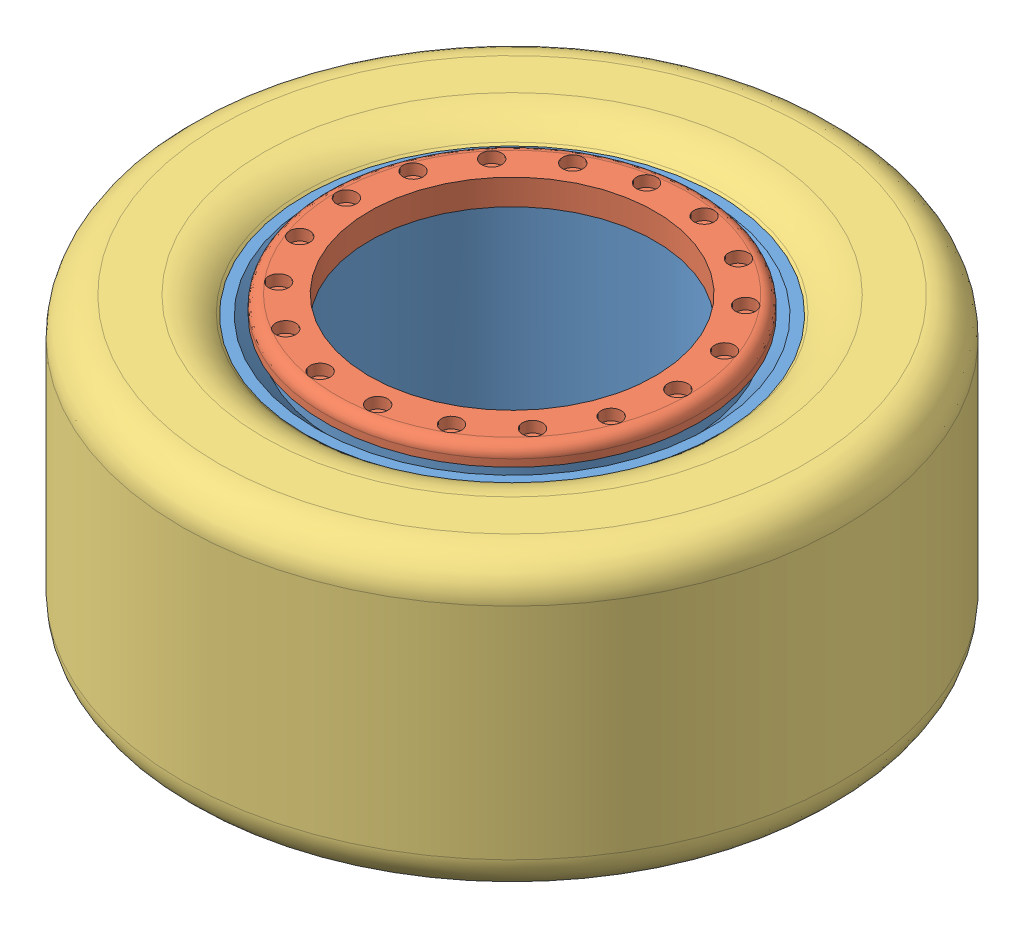
SolidWorks assembly Wheel, configuration Default. Lengths in mm.
Overall size (180 80.5 180).
4 component instances, 3 part files, 9 mates.
Components (placement in the parent):
- Hub-1: Hub [Default] at origin size (113 70.5 113)
- Hub_cover-1: Hub_cover [Default] at (0 70.5 0) x (0.173648 0 -0.984808) z (0.984808 0 0.173648) size (102 7 102)
- Hub_cover-2: Hub_cover [Default] x (-0.766044 0 0.642788) z (0.642788 0 0.766044) size (102 7 102)
- Tire-1: Tire [Default] at (0 -4.75 0) size (180 80 180)
Mates (geometry in assembly coordinates):
- Concentric1: concentric aligned: cylinder of Hub-1 through (0 0 0) axis (0 -1 0) radius 48.5; cylinder of Hub_cover-1 through (0 75.5 0) axis (0 -1 0) radius 39
- Concentric2: concentric anti-aligned: cylinder of Hub-1 through (0 0 0) axis (0 -1 0) radius 48.5; cylinder of Hub_cover-2 through (0 -5 0) axis (0 1 0) radius 39
- Coincident1: coincident anti-aligned: plane of Hub-1 through (0 70.5 -48.5) normal (0 1 0); plane of Hub_cover-1 through (0 70.5 0) normal (0 -1 0)
- Coincident2: coincident anti-aligned: plane of Hub-1 through (0 0 -48.5) normal (0 -1 0); plane of Hub_cover-2 through (0 0 0) normal (0 1 0)
- Concentric4: concentric anti-aligned: cylinder of Hub-1 through (7.8576 65.5 -44.5626) axis (0 1 0) radius 1.5; cylinder of Hub_cover-1 through (7.8576 75.5 -44.5626) axis (0 -1 0) radius 1.5
- Concentric5: concentric anti-aligned: cylinder of Hub-1 through (7.8576 5 -44.5626) axis (0 -1 0) radius 1.5; cylinder of Hub_cover-2 through (7.8576 -5 -44.5626) axis (0 1 0) radius 1.5
- Concentric6: concentric aligned: cylinder of Hub-1 through (0 0 0) axis (0 -1 0) radius 44.5; cylinder of Tire-1 through (0 75.25 0) axis (0 -1 0) radius 44.5
- Coincident4: coincident anti-aligned: plane of Tire-1 through (0 35.25 0) normal (0 -1 0)
- Coincident5: coincident aligned: plane of Tire-1 through (0 -4.75 0) normal (0 0 1)
